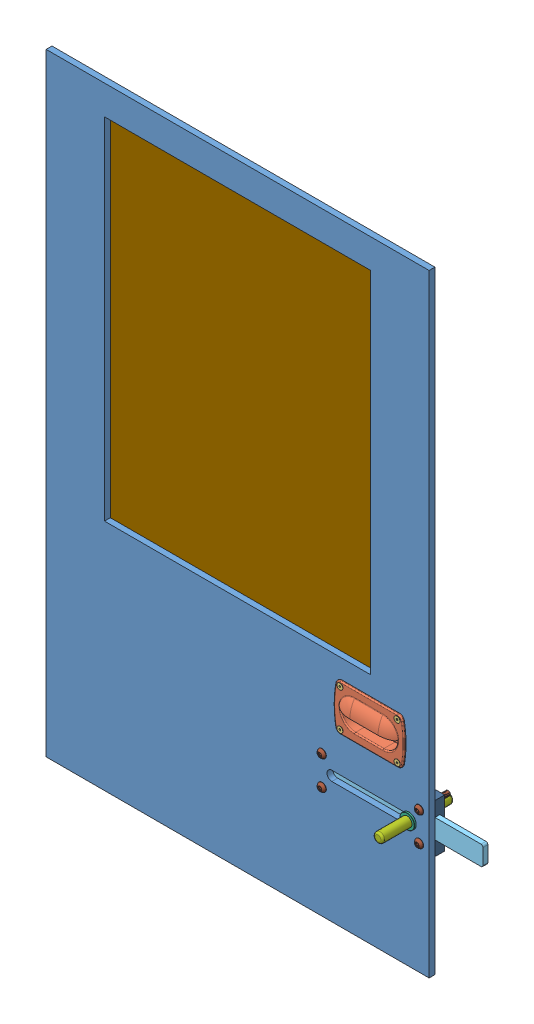
SolidWorks assembly DoorAssem, configuration Default. Lengths in mm.
Overall size (562.72 800 92.71).
25 component instances, 12 part files, 59 mates.
Components (placement in the parent):
- DoorMAX-1: DoorMAX [Default] at (272.5219 309.4622 687.1454) size (500 800 7.62)
- RecessedPullHandle-1: RecessedPullHandle [13155A61] at (446.3219 159.3982 697.3054) size (92.08 60.32 25.4)
- 6-32HexBolt-1: 6-32HexBolt [91263A518] at (408.9839 183.7822 688.2884) x (0.866025 0.5 0) z (0 0 1) size (7.8 7.8 19.48)
- 6-32HexBolt-2: 6-32HexBolt [91263A518] at (483.6599 183.7822 688.2884) x (0.866025 0.5 0) z (0 0 1) size (7.8 7.8 19.48)
- 6-32HexBolt-4: 6-32HexBolt [91263A518] at (408.9839 135.0142 688.2884) x (0.866025 0.5 0) z (0 0 1) size (7.8 7.8 19.48)
- 6-32HexBolt-6: 6-32HexBolt [91263A518] at (483.6599 135.0142 688.2884) x (0.866025 0.5 0) z (0 0 1) size (7.8 7.8 19.48)
- 6-32HexNut-1: 6-32HexNut [93776A370] at (483.6599 183.7822 682.7798) x (-0.866025 -0.5 0) z (0 0 -1) size (10.72 10.72 4.5)
- 6-32HexNut-2: 6-32HexNut [93776A370] at (408.9839 183.7822 682.7798) x (-0.866025 -0.5 0) z (0 0 -1) size (10.72 10.72 4.5)
- 6-32HexNut-4: 6-32HexNut [93776A370] at (408.9839 135.0142 682.7798) x (-0.866025 -0.5 0) z (0 0 -1) size (10.72 10.72 4.5)
- 6-32HexNut-6: 6-32HexNut [93776A370] at (483.6599 135.0142 682.7798) x (-0.866025 -0.5 0) z (0 0 -1) size (10.72 10.72 4.5)
- LatchLever-1: LatchLever [Default] at (483.6239 74.5818 680.7954) x (0.999999 -0.001546 0) z (0 0 1) size (203.2 25.4 6.35)
- WasherID0.25-1: WasherID0.25 [Default] at (496.3239 74.5622 694.7654) size (19.05 19.05 2.54)
- PullHandle-1: PullHandle [Default] at (496.3239 74.5622 697.3054) x (0.432327 -0.901717 0) z (0 0 1) size (12.7 12.7 38.1)
- ThreadedRod0.25-20-1: ThreadedRod0.25-20 [90322A648] at (496.3239 74.5622 703.6554) x (0.967956 0.25112 0) z (0 0 1) size (6.49 6.42 52.37)
- PullHandle-2: PullHandle [Default] at (496.3239 74.5622 680.7954) x (0.588923 -0.808189 0) z (0 0 -1) size (12.7 12.7 38.1)
- PolycarbonateWindow-1: PolycarbonateWindow [Default] at (272.4589 442.7622 680.7954) size (360.43 469.9 6.35)
- LeverMount-1: LeverMount [Default] at (446.3219 74.5622 687.1454) x (-1 0 0) z (0 0 -1) size (152.4 63.5 12.7)
- 0.25-20BoltRound-1: 0.25-20BoltRound [97763A348] at (509.8219 93.6122 677.3918) x (0.99795 0.064005 0) z (0 0 1) size (11.1 11.1 42.18)
- 0.25-20NutFlange-1: 0.25-20NutFlange [93776A421] at (509.8219 93.6122 668.4923) x (-1 0 0) z (0 0 -1) size (15.08 15.08 6.46)
- 0.25-20BoltRound-2: 0.25-20BoltRound [97763A348] at (509.8219 55.5122 677.3918) x (0.278864 -0.960331 0) z (0 0 1) size (11.1 11.1 42.18)
- 0.25-20BoltRound-5: 0.25-20BoltRound [97763A348] at (382.8219 55.5122 677.3918) x (0.278864 -0.960331 0) z (0 0 1) size (11.1 11.1 42.18)
- 0.25-20BoltRound-7: 0.25-20BoltRound [97763A348] at (382.8219 93.6122 677.3918) x (0.107867 -0.994165 0) z (0 0 1) size (11.1 11.1 42.18)
- 0.25-20NutFlange-2: 0.25-20NutFlange [93776A421] at (382.8219 93.6122 668.4923) x (-0.987351 -0.158553 0) z (0 0 -1) size (15.08 15.08 6.46)
- 0.25-20NutFlange-4: 0.25-20NutFlange [93776A421] at (382.8219 55.5122 668.4923) x (-0.959125 -0.282984 0) z (0 0 -1) size (15.08 15.08 6.46)
- 0.25-20NutFlange-6: 0.25-20NutFlange [93776A421] at (509.8219 55.5122 668.4923) x (-0.928571 -0.371154 0) z (0 0 -1) size (15.08 15.08 6.46)
Mates (geometry in assembly coordinates):
- Coincident1: coincident anti-aligned: plane of DoorMAX-1 through (272.5219 309.4622 694.7654) normal (0 0 1); plane of RecessedPullHandle-1 through (483.9471 183.2107 694.7654) normal (0 0 -1)
- Coincident2: coincident anti-aligned: plane of DoorMAX-1 through (428.7959 180.7342 694.7654) normal (0 -1 0); plane of RecessedPullHandle-1 through (463.8479 180.7342 570.538) normal (0 1 0)
- Concentric1: concentric anti-aligned: cylinder of DoorMAX-1 through (463.8479 159.3982 694.7654) axis (0 0 -1) radius 21.336; cylinder of RecessedPullHandle-1 through (463.8479 159.3982 570.538) axis (0 0 1) radius 21.336
- Concentric2: concentric anti-aligned: cylinder of DoorMAX-1 through (408.9839 183.7822 694.7654) axis (0 0 -1) radius 1.905; cylinder of 6-32HexBolt-1 through (408.9839 183.7822 697.8134) axis (0 0 1) radius 3.8989
- Distance1: distance = 8.382 mm aligned: plane of 6-32HexBolt-1 through (408.1076 185.3 678.7634) normal (0 0 -1); plane of DoorMAX-1 through (272.5219 309.4622 687.1454) normal (0 0 -1)
- Parallel1: parallel aligned: plane of RecessedPullHandle-1 through (408.6966 189.5607 694.7654) normal (0 1 0); plane of 6-32HexBolt-1 through (408.411 182.79 696.0888) normal (0 1 0)
- Concentric4: concentric anti-aligned: cylinder of DoorMAX-1 through (483.6599 183.7822 694.7654) axis (0 0 -1) radius 1.905; cylinder of 6-32HexBolt-2 through (483.6599 183.7822 697.8134) axis (0 0 1) radius 3.8989
- Distance2: distance = 8.382 mm aligned: plane of 6-32HexBolt-2 through (482.7836 185.3 678.7634) normal (0 0 -1); plane of DoorMAX-1 through (272.5219 309.4622 687.1454) normal (0 0 -1)
- Parallel3: parallel aligned: plane of RecessedPullHandle-1 through (408.6966 189.5607 694.7654) normal (0 1 0); plane of 6-32HexBolt-2 through (483.087 182.79 696.0888) normal (0 1 0)
- Concentric5: concentric anti-aligned: cylinder of DoorMAX-1 through (408.9839 135.0142 694.7654) axis (0 0 -1) radius 1.905; cylinder of 6-32HexBolt-4 through (408.9839 135.0142 697.8134) axis (0 0 1) radius 3.8989
- Distance3: distance = 8.382 mm aligned: plane of 6-32HexBolt-4 through (408.1076 136.532 678.7634) normal (0 0 -1); plane of DoorMAX-1 through (272.5219 309.4622 687.1454) normal (0 0 -1)
- Parallel4: parallel aligned: plane of RecessedPullHandle-1 through (408.6966 189.5607 694.7654) normal (0 1 0); plane of 6-32HexBolt-4 through (408.411 134.022 696.0888) normal (0 1 0)
- Concentric6: concentric anti-aligned: cylinder of DoorMAX-1 through (483.6599 135.0142 694.7654) axis (0 0 -1) radius 1.905; cylinder of 6-32HexBolt-6 through (483.6599 135.0142 697.8134) axis (0 0 1) radius 3.8989
- Distance4: distance = 8.382 mm aligned: plane of 6-32HexBolt-6 through (482.7836 136.532 678.7634) normal (0 0 -1); plane of DoorMAX-1 through (272.5219 309.4622 687.1454) normal (0 0 -1)
- Parallel5: parallel aligned: plane of RecessedPullHandle-1 through (408.6966 189.5607 694.7654) normal (0 1 0); plane of 6-32HexBolt-6 through (483.087 134.022 696.0888) normal (0 1 0)
- Coincident5: coincident anti-aligned: plane of DoorMAX-1 through (272.5219 309.4622 687.1454) normal (0 0 -1); plane of 6-32HexNut-1 through (481.3685 187.7509 687.1454) normal (0 0 1)
- Concentric7: concentric anti-aligned: circle of 6-32HexBolt-2; cylinder of 6-32HexNut-1 through (483.6599 183.7822 685.342) axis (0 0 1) radius 5.3578
- Parallel6: parallel anti-aligned: plane of RecessedPullHandle-1 through (463.8479 180.7342 570.538) normal (0 1 0); plane of 6-32HexNut-1 through (485.9512 179.8134 687.1454) normal (0 -1 0)
- Coincident7: coincident anti-aligned: plane of DoorMAX-1 through (272.5219 309.4622 687.1454) normal (0 0 -1); plane of 6-32HexNut-2 through (406.6925 187.7509 687.1454) normal (0 0 1)
- Concentric8: concentric anti-aligned: circle of 6-32HexBolt-1; cylinder of 6-32HexNut-2 through (408.9839 183.7822 685.342) axis (0 0 1) radius 5.3578
- Parallel7: parallel anti-aligned: plane of RecessedPullHandle-1 through (463.8479 180.7342 570.538) normal (0 1 0); plane of 6-32HexNut-2 through (411.2752 179.8134 687.1454) normal (0 -1 0)
- Coincident8: coincident anti-aligned: plane of DoorMAX-1 through (272.5219 309.4622 687.1454) normal (0 0 -1); plane of 6-32HexNut-4 through (406.6925 138.9829 687.1454) normal (0 0 1)
- Concentric9: concentric anti-aligned: circle of 6-32HexBolt-4; cylinder of 6-32HexNut-4 through (408.9839 135.0142 685.342) axis (0 0 1) radius 5.3578
- Parallel8: parallel anti-aligned: plane of RecessedPullHandle-1 through (463.8479 180.7342 570.538) normal (0 1 0); plane of 6-32HexNut-4 through (411.2752 131.0454 687.1454) normal (0 -1 0)
- Coincident9: coincident anti-aligned: plane of DoorMAX-1 through (272.5219 309.4622 687.1454) normal (0 0 -1); plane of 6-32HexNut-6 through (481.3685 138.9829 687.1454) normal (0 0 1)
- Concentric10: concentric anti-aligned: circle of 6-32HexBolt-6; cylinder of 6-32HexNut-6 through (483.6599 135.0142 685.342) axis (0 0 1) radius 5.3578
- Parallel9: parallel anti-aligned: plane of RecessedPullHandle-1 through (463.8479 180.7342 570.538) normal (0 1 0); plane of 6-32HexNut-6 through (485.9512 131.0454 687.1454) normal (0 -1 0)
- Coincident10: coincident anti-aligned: plane of DoorMAX-1 through (272.5219 309.4622 687.1454) normal (0 0 -1); plane of LatchLever-1 through (582.6681 64.2686 687.1454) normal (0 0 1)
- Coincident11: coincident anti-aligned: plane of DoorMAX-1 through (272.5219 309.4622 694.7654) normal (0 0 1); plane of WasherID0.25-1 through (496.3239 74.5622 694.7654) normal (0 0 -1)
- Concentric11: concentric aligned: cylinder of LatchLever-1 through (496.3239 74.5622 687.1454) axis (0 0 -1) radius 3.175; cylinder of WasherID0.25-1 through (496.3239 74.5622 697.3054) axis (0 0 -1) radius 3.2639
- Coincident12: coincident anti-aligned: plane of WasherID0.25-1 through (496.3239 74.5622 697.3054) normal (0 0 1); plane of PullHandle-1 through (496.3239 74.5622 697.3054) normal (0 0 -1)
- Concentric12: concentric aligned: cylinder of WasherID0.25-1 through (496.3239 74.5622 697.3054) axis (0 0 -1) radius 9.525; cylinder of PullHandle-1 through (496.3239 74.5622 735.4054) axis (0 0 -1) radius 6.35
- Tangent1: tangent anti-aligned: plane of DoorMAX-1 through (497.1219 68.2122 694.7654) normal (0 1 0); cylinder of PullHandle-1 through (496.3239 74.5622 735.4054) axis (0 0 -1) radius 6.35
- Distance5: distance = 6.35 mm anti-aligned: plane of PullHandle-1 through (496.3239 74.5622 722.7054) normal (0 0 -1); plane of ThreadedRod0.25-20-1 through (496.3239 74.5622 729.0554) normal (0 0 1)
- Concentric13: concentric anti-aligned: cylinder of PullHandle-1 through (496.3239 74.5622 735.4054) axis (0 0 -1) radius 6.35; circle of ThreadedRod0.25-20-1
- Coincident14: coincident anti-aligned: plane of LatchLever-1 through (582.6681 64.2686 680.7954) normal (0 0 -1); plane of PullHandle-2 through (496.3239 74.5622 680.7954) normal (0 0 1)
- Concentric14: concentric anti-aligned: cylinder of PullHandle-1 through (496.3239 74.5622 735.4054) axis (0 0 -1) radius 6.35; cylinder of PullHandle-2 through (496.3239 74.5622 642.6954) axis (0 0 1) radius 6.35
- Coincident15: coincident anti-aligned: plane of DoorMAX-1 through (272.5219 309.4622 687.1454) normal (0 0 -1); plane of PolycarbonateWindow-1 through (272.4589 442.7622 687.1454) normal (0 0 1)
- Distance6: distance = 6.35 mm anti-aligned: plane of PolycarbonateWindow-1 through (92.2459 677.7122 687.1454) normal (0 1 0); plane of DoorMAX-1 through (98.7219 671.3622 694.7654) normal (0 -1 0)
- Distance7: distance = 6.35 mm anti-aligned: plane of PolycarbonateWindow-1 through (452.6719 677.7122 687.1454) normal (1 0 0); plane of DoorMAX-1 through (446.3219 671.3622 694.7654) normal (-1 0 0)
- Tangent2: tangent anti-aligned: cylinder of PullHandle-2 through (496.3239 74.5622 642.6954) axis (0 0 1) radius 6.35; plane of LeverMount-1 through (497.1219 68.2122 674.4454) normal (0 1 0)
- Coincident18: coincident aligned: plane of DoorMAX-1 through (522.5219 709.4622 694.7654) normal (1 0 0); plane of LeverMount-1 through (522.5219 106.3122 674.4454) normal (1 0 0)
- Coincident19: coincident anti-aligned: plane of DoorMAX-1 through (272.5219 309.4622 687.1454) normal (0 0 -1); plane of LeverMount-1 through (446.3219 74.5622 687.1454) normal (0 0 1)
- Concentric19: concentric aligned: cylinder of LeverMount-1 through (509.8219 93.6122 674.4454) axis (0 0 1) radius 3.175; cylinder of 0.25-20BoltRound-1 through (509.8219 93.6122 698.1182) axis (0 0 1) radius 3.175
- Coincident25: coincident anti-aligned: plane of DoorMAX-1 through (272.5219 309.4622 694.7654) normal (0 0 1); plane of 0.25-20BoltRound-1 through (515.3604 93.9674 694.7654) normal (0 0 -1)
- Coincident26: coincident anti-aligned: plane of LeverMount-1 through (446.3219 74.5622 674.4454) normal (0 0 -1); plane of 0.25-20NutFlange-1 through (515.3781 103.2359 674.4454) normal (0 0 1)
- Concentric20: concentric aligned: cylinder of 0.25-20BoltRound-1 through (509.8219 93.6122 698.1182) axis (0 0 1) radius 5.5499; cylinder of 0.25-20NutFlange-1 through (509.8219 93.6122 672.007) axis (0 0 1) radius 7.5406
- Concentric21: concentric anti-aligned: cylinder of DoorMAX-1 through (509.8219 55.5122 694.7654) axis (0 0 -1) radius 3.175; cylinder of 0.25-20BoltRound-2 through (509.8219 55.5122 698.1182) axis (0 0 1) radius 3.175
- Coincident27: coincident anti-aligned: plane of DoorMAX-1 through (272.5219 309.4622 694.7654) normal (0 0 1); plane of 0.25-20BoltRound-2 through (511.3695 50.1824 694.7654) normal (0 0 -1)
- Concentric23: concentric anti-aligned: cylinder of DoorMAX-1 through (382.8219 55.5122 694.7654) axis (0 0 -1) radius 3.175; cylinder of 0.25-20BoltRound-5 through (382.8219 55.5122 698.1182) axis (0 0 1) radius 3.175
- Coincident29: coincident anti-aligned: plane of DoorMAX-1 through (272.5219 309.4622 694.7654) normal (0 0 1); plane of 0.25-20BoltRound-5 through (384.3695 50.1824 694.7654) normal (0 0 -1)
- Concentric24: concentric anti-aligned: cylinder of DoorMAX-1 through (382.8219 93.6122 694.7654) axis (0 0 -1) radius 3.175; cylinder of 0.25-20BoltRound-7 through (382.8219 93.6122 698.1182) axis (0 0 1) radius 3.175
- Coincident30: coincident anti-aligned: plane of DoorMAX-1 through (272.5219 309.4622 694.7654) normal (0 0 1); plane of 0.25-20BoltRound-7 through (383.4205 88.0946 694.7654) normal (0 0 -1)
- Coincident31: coincident anti-aligned: plane of LeverMount-1 through (446.3219 74.5622 674.4454) normal (0 0 -1); plane of 0.25-20NutFlange-2 through (386.782 103.9951 674.4454) normal (0 0 1)
- Concentric25: concentric aligned: circle of 0.25-20BoltRound-7; cylinder of 0.25-20NutFlange-2 through (382.8219 93.6122 672.007) axis (0 0 1) radius 7.5406
- Coincident32: coincident anti-aligned: plane of LeverMount-1 through (446.3219 74.5622 674.4454) normal (0 0 -1); plane of 0.25-20NutFlange-4 through (385.4277 66.3148 674.4454) normal (0 0 1)
- Concentric26: concentric aligned: circle of 0.25-20BoltRound-5; cylinder of 0.25-20NutFlange-4 through (382.8219 55.5122 672.007) axis (0 0 1) radius 7.5406
- Coincident33: coincident anti-aligned: plane of LeverMount-1 through (446.3219 74.5622 674.4454) normal (0 0 -1); plane of 0.25-20NutFlange-6 through (511.4094 66.5107 674.4454) normal (0 0 1)
- Concentric27: concentric aligned: circle of 0.25-20BoltRound-2; cylinder of 0.25-20NutFlange-6 through (509.8219 55.5122 672.007) axis (0 0 1) radius 7.5406
